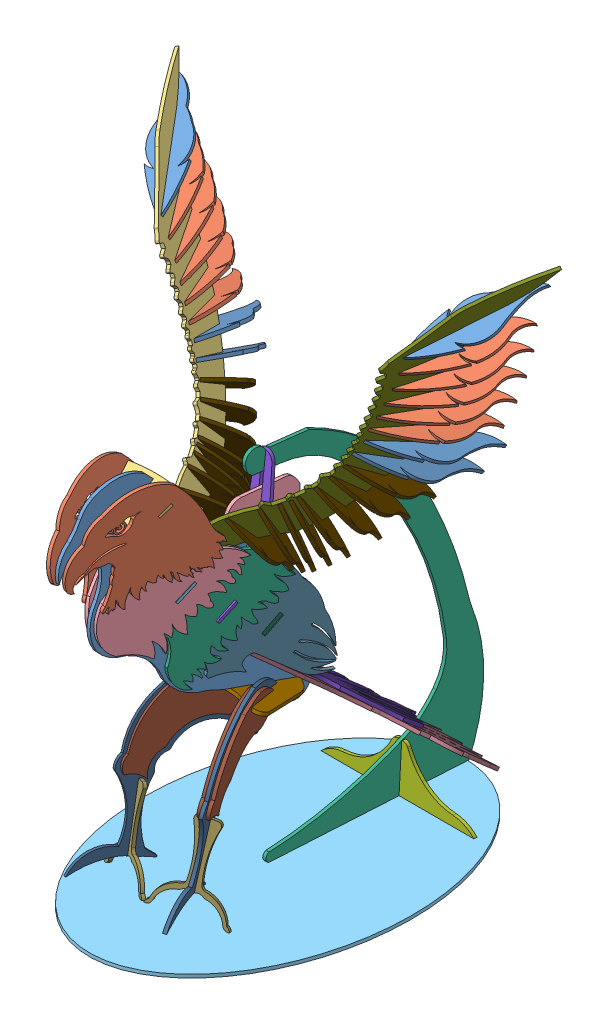
SolidWorks assembly _Assy, Eagle 03, configuration Default. Lengths in mm.
Overall size (190.84 278.18 211.69).
63 component instances, 26 part files, 130 mates.
Components (placement in the parent):
- Eagle-03-Face Plt-1: Eagle-03-Face Plt [Default] at (4.5464 2.0821 -8.328) size (1.52 133.89 123.29)
- Eagle-03-Face-3: Eagle-03-Face [Default] at (18.2617 -23.9605 -54.6337) x (0.981866 -0.103641 0.158737) z (-0.158737 0.008301 0.987286) size (1.52 51.83 68.44)
- Eagle-03-Face Plt, Connector-1: Eagle-03-Face Plt, Connector [Default] at (4.5464 6.6649 -5.3358) x (1 0 0) z (0 0.837329 0.546699) size (25.62 23.51 1.52)
- Eagle-03-Face-4: Eagle-03-Face [Default] at (-8.9705 -24.1185 -54.3918) x (0.981866 0.103641 -0.158737) z (0.158737 0.008301 0.987286) size (1.52 51.83 68.44)
- Part3^_Assy, Eagle 03-1: Part3^_Assy, Eagle 03 [Default] at (18.2617 -23.9605 -54.6337) x (-0.158737 0.008301 0.987286) z (-0.981866 0.103641 -0.158737) size (64.01 49.83 1.52) (virtual)
- Part4^_Assy, Eagle 03-1: Part4^_Assy, Eagle 03 [Default] at (4.5464 -26.2675 -30.5298) x (-1 0 0) z (0 -0.7873 -0.61657) size (21.81 39.99 1.52) (virtual)
- Part5^_Assy, Eagle 03-1: Part5^_Assy, Eagle 03 [Default] at (16.7654 -23.8026 -54.8756) x (-0.158737 0.008301 0.987286) z (-0.981866 0.103641 -0.158737) size (61.68 57.86 1.52) (virtual)
- MirrorPart5^_Assy, Eagle 03-2: MirrorPart5^_Assy, Eagle 03 [Default] at (-6.1486 -23.8026 -54.8756) x (0.158737 0.008301 0.987286) z (-0.981866 -0.103641 0.158737) size (61.68 57.86 1.52) (virtual)
- Part3^_Assy, Eagle 03-2: Part3^_Assy, Eagle 03 [Default] at (-6.1486 -23.8026 -54.8756) x (0.158737 0.008301 0.987286) z (-0.981866 -0.103641 0.158737) size (64.01 49.83 1.52) (virtual)
- Part7^_Assy, Eagle 03-1: Part7^_Assy, Eagle 03 [Default] at (4.5464 -45.8899 -47.7408) x (-1 0 0) z (0 -0.772669 -0.63481) size (23.73 45.97 1.52) (virtual)
- Part9^_Assy, Eagle 03-1: Part9^_Assy, Eagle 03 [Default] at (4.5464 -62.0946 14.0717) x (1 0 0) z (0 0.944143 -0.329537) size (40.67 40.1 1.52) (virtual)
- Part10^_Assy, Eagle 03-1: Part10^_Assy, Eagle 03 [Default] at (41.0348 -67.1746 -0.4828) x (0 -0.944143 0.329537) z (0.921165 -0.128247 -0.367435) size (82.99 56.69 1.52) (virtual)
- Part11^_Assy, Eagle 03-1: Part11^_Assy, Eagle 03 [Default] at (42.4386 -67.37 -1.0428) x (0 -0.944143 0.329537) z (0.921165 -0.128247 -0.367435) size (42.47 43.2 1.52) (virtual)
- Part12^_Assy, Eagle 03-1: Part12^_Assy, Eagle 03 [Default] at (22.8492 -76.282 -42.8953) x (0.044494 0.972658 -0.227942) z (0.386621 0.193623 0.901684) size (38.71 31.92 1.52) (virtual)
- Part11^_Assy, Eagle 03-2: Part11^_Assy, Eagle 03 [Default] at (-33.2257 -67.5654 -1.6027) x (0 -0.944143 0.329537) z (0.921165 0.128247 0.367435) size (42.47 43.2 1.52) (virtual)
- Part10^_Assy, Eagle 03-2: Part10^_Assy, Eagle 03 [Default] at (-31.8218 -67.37 -1.0428) x (0 -0.944143 0.329537) z (0.921165 0.128247 0.367435) size (82.99 56.69 1.52) (virtual)
- Part12^_Assy, Eagle 03-2: Part12^_Assy, Eagle 03 [Default] at (-12.8217 -75.9869 -41.5211) x (-0.044494 0.972658 -0.227942) z (0.386621 -0.193623 -0.901684) size (38.71 31.92 1.52) (virtual)
- Part11^_Assy, Eagle 03-3: Part11^_Assy, Eagle 03 [Default] at (39.9279 -66.7475 0.7408) x (0 -0.944143 0.329537) z (0.921165 -0.128247 -0.367435) size (42.47 43.2 1.52) (virtual)
- Part11^_Assy, Eagle 03-4: Part11^_Assy, Eagle 03 [Default] at (-30.7149 -66.9429 0.1808) x (0 -0.944143 0.329537) z (0.921165 0.128247 0.367435) size (42.47 43.2 1.52) (virtual)
- Eagle-03-Tail Feathers-1: Eagle-03-Tail Feathers [Default] at (5.3141 -107.6736 -104.5479) x (1 0.000049 0.000057) z (0 0.75999 -0.649935) size (91.35 114.83 1.52)
- Part13^_Assy, Eagle 03-1: Part13^_Assy, Eagle 03 [Default] at (15.269 -23.6446 -55.1175) x (-0.158737 0.008301 0.987286) z (-0.981866 0.103641 -0.158737) size (63.31 61.71 1.52) (virtual)
- Part13^_Assy, Eagle 03-2: Part13^_Assy, Eagle 03 [Default] at (-3.1558 -23.4867 -55.3594) x (0.158737 0.008301 0.987286) z (-0.981866 -0.103641 0.158737) size (63.31 61.71 1.52) (virtual)
- Part14^_Assy, Eagle 03-1: Part14^_Assy, Eagle 03 [Default] at (4.5464 -63.6501 -66.7331) x (-1 0 0) z (0 -0.747542 -0.664215) size (19.33 35.27 2.54) (virtual)
- Eagle-03-Wing-1: Eagle-03-Wing [Default] at (47.6613 31.141 -82.0922) x (0.53253 0.453967 -0.714371) z (0.845247 -0.32948 0.420715) size (164.91 76.09 1.52)
- Part6^_Assy, Eagle 03-1: Part6^_Assy, Eagle 03 [Default] at (5.3141 -106.5154 -105.5384) x (1 0.000049 0.000057) z (0 0.75999 -0.649935) size (56.42 90.79 1.52) (virtual)
- Eagle-03-Wing, Feather 01-1: Eagle-03-Wing, Feather 01 [Default] at (27.2198 17.4276 -51.7634) x (-0.845247 0.32948 -0.420715) z (0.523324 0.351078 -0.776451) size (16.36 41.94 1.52)
- Eagle-03-Wing, Feather 01-2: Eagle-03-Wing, Feather 01 [Default] at (29.1257 18.0081 -55.1379) x (-0.845247 0.32948 -0.420715) z (0.533315 0.470534 -0.702974) size (16.36 41.94 1.52)
- Eagle-03-Wing, Feather 01-5: Eagle-03-Wing, Feather 01 [Default] at (31.1805 19.9433 -57.7505) x (-0.845247 0.32948 -0.420715) z (0.532756 0.58084 -0.615464) size (16.36 41.94 1.52)
- Eagle-03-Wing, Feather 01-6: Eagle-03-Wing, Feather 01 [Default] at (33.1888 22.3762 -59.88) x (-0.845247 0.32948 -0.420715) z (0.521633 0.679638 -0.515744) size (16.36 41.94 1.52)
- Eagle-03-Wing, Feather 01-7: Eagle-03-Wing, Feather 01 [Default] at (35.1835 24.952 -61.8704) x (-0.845247 0.32948 -0.420715) z (0.50015 0.765007 -0.405727) size (16.36 41.94 1.52)
- Eagle-03-Wing, Feather 02-1: Eagle-03-Wing, Feather 02 [Default] at (37.2021 27.7302 -63.7501) x (-0.845247 0.32948 -0.420715) z (0.468765 0.835141 -0.287748) size (17.91 55.77 1.52)
- Eagle-03-Wing, Feather 02-2: Eagle-03-Wing, Feather 02 [Default] at (39.2678 30.7754 -65.5155) x (-0.845247 0.32948 -0.420715) z (0.428068 0.88874 -0.164008) size (17.91 55.77 1.52)
- Eagle-03-Wing, Feather 03-1: Eagle-03-Wing, Feather 03 [Default] at (41.4186 34.1243 -67.2139) x (-0.845247 0.32948 -0.420715) z (0.378864 0.924713 -0.036982) size (16.4 49.51 1.52)
- Eagle-03-Wing, Feather 03-2: Eagle-03-Wing, Feather 03 [Default] at (43.5314 37.9912 -68.4303) x (-0.845247 0.32948 -0.420715) z (0.322091 0.942336 0.090881) size (16.4 49.51 1.52)
- Eagle-03-Wing, Feather 03-3: Eagle-03-Wing, Feather 03 [Default] at (45.8003 42.2995 -69.6147) x (-0.845247 0.32948 -0.420715) z (0.259027 0.941242 0.216723) size (16.4 49.51 1.52)
- Eagle-03-Wing, Feather 03-4: Eagle-03-Wing, Feather 03 [Default] at (48.4967 47.3173 -71.1023) x (-0.845247 0.32948 -0.420715) z (0.190776 0.921474 0.338364) size (16.4 49.51 1.52)
- Eagle-03-Wing, Feather 03-5: Eagle-03-Wing, Feather 03 [Default] at (51.3336 53.2849 -72.1283) x (-0.845247 0.32948 -0.420715) z (0.118763 0.883435 0.453253) size (16.4 49.51 1.52)
- Eagle-03-Wing, Feather 02-4: Eagle-03-Wing, Feather 02 [Default] at (52.8567 58.4319 -71.1574) x (-0.845247 0.32948 -0.420715) z (0.044381 0.827863 0.559172) size (17.91 55.77 1.52)
- Eagle-03-Wing, Feather 01-8: Eagle-03-Wing, Feather 01 [Default] at (14.8649 11.7304 -31.4033) x (-0.845247 0.32948 -0.420715) z (0.532146 0.590827 -0.606419) size (16.36 41.94 1.52)
- Eagle-03-Wing, Feather 01-9: Eagle-03-Wing, Feather 01 [Default] at (22.8616 16.0279 -44.1037) x (-0.845247 0.32948 -0.420715) z (0.530699 0.425366 -0.733091) size (16.36 41.94 1.52)
- Eagle-03-Wing, Feather 01-10: Eagle-03-Wing, Feather 01 [Default] at (28.7032 17.932 -54.3485) x (-0.845247 0.32948 -0.420715) z (0.527566 0.389225 -0.755101) size (16.36 41.94 1.52)
- MirrorEagle-03-Wing-2: MirrorEagle-03-Wing [Default] at (-37.0445 31.141 -82.0922) x (-0.53253 0.453967 -0.714371) z (0.845247 0.32948 -0.420715) size (164.91 76.09 1.52)
- Eagle-03-Wing, Feather 01-11: Eagle-03-Wing, Feather 01 [Default] at (-5.0591 12.6308 -32.3274) x (0.845247 0.32948 -0.420715) z (0.532146 -0.590827 0.606419) size (16.36 41.94 1.52)
- Eagle-03-Wing, Feather 01-12: Eagle-03-Wing, Feather 01 [Default] at (-13.0536 16.6761 -45.221) x (0.845247 0.32948 -0.420715) z (0.530699 -0.425366 0.733091) size (16.36 41.94 1.52)
- Eagle-03-Wing, Feather 01-13: Eagle-03-Wing, Feather 01 [Default] at (-17.4006 17.9627 -52.9467) x (0.845247 0.32948 -0.420715) z (0.523324 -0.351078 0.776451) size (16.36 41.94 1.52)
- Eagle-03-Wing, Feather 01-14: Eagle-03-Wing, Feather 01 [Default] at (-18.8904 18.5252 -55.4993) x (0.845247 0.32948 -0.420715) z (0.527566 -0.389225 0.755101) size (16.36 41.94 1.52)
- Eagle-03-Wing, Feather 01-15: Eagle-03-Wing, Feather 01 [Default] at (-19.3217 18.7252 -56.2092) x (0.845247 0.32948 -0.420715) z (0.533315 -0.470534 0.702974) size (16.36 41.94 1.52)
- Eagle-03-Wing, Feather 01-16: Eagle-03-Wing, Feather 01 [Default] at (-21.3756 20.8285 -58.6885) x (0.845247 0.32948 -0.420715) z (0.532756 -0.58084 0.615464) size (16.36 41.94 1.52)
- Eagle-03-Wing, Feather 01-17: Eagle-03-Wing, Feather 01 [Default] at (-23.367 23.412 -60.666) x (0.845247 0.32948 -0.420715) z (0.521633 -0.679638 0.515744) size (16.36 41.94 1.52)
- Eagle-03-Wing, Feather 01-18: Eagle-03-Wing, Feather 01 [Default] at (-25.329 26.1179 -62.4888) x (0.845247 0.32948 -0.420715) z (0.50015 -0.765007 0.405727) size (16.36 41.94 1.52)
- Eagle-03-Wing, Feather 02-5: Eagle-03-Wing, Feather 02 [Default] at (-27.2997 29.0029 -64.1886) x (0.845247 0.32948 -0.420715) z (0.468765 -0.835141 0.287748) size (17.91 55.77 1.52)
- Eagle-03-Wing, Feather 02-6: Eagle-03-Wing, Feather 02 [Default] at (-29.3034 32.1298 -65.7655) x (0.845247 0.32948 -0.420715) z (0.428068 -0.88874 0.164008) size (17.91 55.77 1.52)
- Eagle-03-Wing, Feather 03-6: Eagle-03-Wing, Feather 03 [Default] at (-31.3792 35.5335 -67.2703) x (0.845247 0.32948 -0.420715) z (0.378864 -0.924713 0.036982) size (16.4 49.51 1.52)
- Eagle-03-Wing, Feather 03-7: Eagle-03-Wing, Feather 03 [Default] at (-35.5783 43.734 -69.2845) x (0.845247 0.32948 -0.420715) z (0.259027 -0.941242 -0.216723) size (16.4 49.51 1.52)
- Eagle-03-Wing, Feather 03-8: Eagle-03-Wing, Feather 03 [Default] at (-33.4055 39.4273 -68.2918) x (0.845247 0.32948 -0.420715) z (0.322091 -0.942336 -0.090881) size (16.4 49.51 1.52)
- Eagle-03-Wing, Feather 03-9: Eagle-03-Wing, Feather 03 [Default] at (-38.1706 48.7216 -70.5866) x (0.845247 0.32948 -0.420715) z (0.190776 -0.921474 -0.338364) size (16.4 49.51 1.52)
- Eagle-03-Wing, Feather 03-10: Eagle-03-Wing, Feather 03 [Default] at (-40.8978 54.6313 -71.4375) x (0.845247 0.32948 -0.420715) z (0.118763 -0.883435 -0.453253) size (16.4 49.51 1.52)
- Eagle-03-Wing, Feather 02-7: Eagle-03-Wing, Feather 02 [Default] at (-42.3075 59.6936 -70.3053) x (0.845247 0.32948 -0.420715) z (0.044381 -0.827863 -0.559172) size (17.91 55.77 1.52)
- Part8^_Assy, Eagle 03-1: Part8^_Assy, Eagle 03 [Default] at (6.0704 2.0821 -8.328) x (0 0 -1) z (1 0 0) size (46.26 26.4 1.52) (virtual)
- Eagle-03-Base-1: Eagle-03-Base [Default] at (5.3084 -168.7529 -81.7321) x (1 0 0) z (0 0.05588 0.998437) size (112.54 1.52 180.18)
- Part15^_Assy, Eagle 03-1: Part15^_Assy, Eagle 03 [Default] at (4.5464 -168.7529 -81.7321) x (0 -0.05588 -0.998437) z (1 0 0) size (121.63 175.4 1.52) (virtual)
- Part16^_Assy, Eagle 03-1: Part16^_Assy, Eagle 03 [Default] at (4.5464 -172.0376 -140.4203) x (1 0 0) z (0 0.05588 0.998437) size (72.95 22.35 1.52) (virtual)
- Part17^_Assy, Eagle 03-1: Part17^_Assy, Eagle 03 [Default] at (4.5464 -165.8304 -56.0297) x (-1 0 0) z (0 -0.112979 -0.993597) size (10.18 28.23 1.52) (virtual)
Mates (geometry in assembly coordinates):
- InPlace1: in place: plane of Eagle-03-Face Plt-1 through (6.0704 18.1227 -23.154) normal (0 0.837329 0.546699); plane of ? through (0 2.1071 1.3757) normal (0 0.837329 0.546699); moOrthogonalPlaneRef_w of Eagle-03-Face Plt-1 through (6.0704 18.1227 -23.154) normal (0 0.837329 0.546699); plane of ? through (0 2.1071 1.3757) normal (0 0.546699 -0.837329); plane of Eagle-03-Face Plt-1 through (6.0704 18.1227 -23.154) normal (0 0.837329 0.546699); unknown of ?; plane of Eagle-03-Face Plt-1 through (6.0704 18.0306 -22.7436) normal (0 0.837329 0.546699); unknown of Eagle-03-Face Plt, Connector-1
- Coincident1: coincident aligned: plane of Eagle-03-Face Plt-1; plane of Eagle-03-Face Plt, Connector-1
- Coincident2: coincident aligned: moOrthogonalPlaneRef_w of Eagle-03-Face Plt-1 through (4.5464 6.6649 -5.3358) normal (0 0.546699 -0.837329); plane of Eagle-03-Face Plt, Connector-1 through (4.5464 6.6649 -5.3358) normal (0 0.546699 -0.837329)
- Coincident3: coincident anti-aligned: moOrthogonalPlaneRef_w of Eagle-03-Face Plt-1 through (4.5464 6.6649 -5.3358) normal (-1 0 0); plane of Eagle-03-Face Plt, Connector-1
- Coincident4: coincident anti-aligned: plane of Eagle-03-Face-3 through (17.054 12.2638 -13.9111) normal (0.189575 0.536786 -0.822145); plane of Eagle-03-Face Plt, Connector-1 through (15.5576 13.6978 -13.3199) normal (-0.189575 -0.536786 0.822145)
- Coincident5: coincident anti-aligned: plane of Eagle-03-Face-3 through (18.231 15.5967 -19.0158) normal (0 0.837329 0.546699); plane of Eagle-03-Face Plt, Connector-1 through (5.3938 -29.841 50.5768) normal (0 -0.837329 -0.546699)
- Coincident6: coincident aligned: plane of Eagle-03-Face-3 through (15.2141 -12.4677 -18.6782) normal (0.981866 -0.103641 0.158737); plane of Eagle-03-Face Plt, Connector-1 through (17.054 13.5399 -13.0779) normal (0.981866 -0.103641 0.158737)
- Coincident7: coincident anti-aligned: plane of Eagle-03-Face Plt, Connector-1 through (-2.5722 7.4746 -3.7883) normal (-0.981866 -0.103641 0.158737); plane of Eagle-03-Face-4 through (-2.9302 -12.3098 -18.9201) normal (0.981866 0.103641 -0.158737)
- Coincident8: coincident anti-aligned: plane of Eagle-03-Face Plt, Connector-1 through (5.3938 -28.5649 51.41) normal (0 0.837329 0.546699); plane of Eagle-03-Face-4 through (-4.77 13.6978 -13.3199) normal (0 -0.837329 -0.546699)
- Coincident10: coincident anti-aligned: plane of Eagle-03-Face Plt, Connector-1 through (-4.77 13.6978 -13.3199) normal (0.189575 -0.536786 0.822145); plane of Eagle-03-Face-4 through (-4.77 12.4217 -14.153) normal (-0.189575 0.536786 -0.822145)
- InPlace2: in place: plane of ? through (12.1937 -12.3098 -18.9201) normal (-0.981866 0.103641 -0.158737); plane of ? through (10.0593 -1.0618 1.6263) normal (-0.981866 0.103641 -0.158737); plane of ? through (12.1937 -12.3098 -18.9201) normal (-0.981866 0.103641 -0.158737); unknown of ?; plane of ? through (12.1937 -12.3098 -18.9201) normal (-0.981866 0.103641 -0.158737); unknown of ?; plane of Eagle-03-Face-3 through (13.7177 -12.3098 -18.9201) normal (-0.981866 0.103641 -0.158737); unknown of Part3^_Assy, Eagle 03-1
- Coincident12: coincident aligned: plane of Eagle-03-Face-3; plane of Part3^_Assy, Eagle 03-1
- Coincident13: coincident aligned: moOrthogonalPlaneRef_w of Eagle-03-Face-3 through (18.2617 -23.9605 -54.6337) normal (0.103641 0.99458 0.008301); plane of Part3^_Assy, Eagle 03-1
- Coincident14: coincident anti-aligned: moOrthogonalPlaneRef_w of Eagle-03-Face-3 through (18.2617 -23.9605 -54.6337) normal (0.158737 -0.008301 -0.987286); plane of Part3^_Assy, Eagle 03-1
- InPlace3: in place: plane of Eagle-03-Face Plt-1 through (6.0704 -14.2584 -45.8643) normal (0 -0.7873 -0.61657); plane of ? through (0 -31.1016 -24.3571) normal (0 -0.7873 -0.61657); plane of Eagle-03-Face Plt-1 through (6.0704 -14.2584 -45.8643) normal (0 -0.7873 -0.61657); unknown of ?; plane of Eagle-03-Face Plt-1 through (6.0704 -14.2584 -45.8643) normal (0 -0.7873 -0.61657); unknown of ?; plane of Eagle-03-Face Plt-1 through (6.0704 -14.2584 -45.8643) normal (0 -0.7873 -0.61657); unknown of Part4^_Assy, Eagle 03-1
- Coincident15: coincident aligned: plane of Eagle-03-Face Plt-1; plane of Part4^_Assy, Eagle 03-1
- Coincident16: coincident aligned: moOrthogonalPlaneRef_w of Eagle-03-Face Plt-1 through (4.5464 -26.2675 -30.5298) normal (0 0.61657 -0.7873); plane of Part4^_Assy, Eagle 03-1
- Coincident17: coincident anti-aligned: moOrthogonalPlaneRef_w of Eagle-03-Face Plt-1 through (4.5464 -26.2675 -30.5298) normal (1 0 0); plane of Part4^_Assy, Eagle 03-1
- InPlace4: in place: plane of Part3^_Assy, Eagle 03-1 through (5.6608 -52.0671 -4.6424) normal (-0.981866 0.103641 -0.158737); plane of ? through (10.0322 -1.0589 1.6219) normal (-0.981866 0.103641 -0.158737); plane of Part3^_Assy, Eagle 03-1 through (5.6608 -52.0671 -4.6424) normal (-0.981866 0.103641 -0.158737); unknown of ?; plane of Part3^_Assy, Eagle 03-1 through (5.6608 -52.0671 -4.6424) normal (-0.981866 0.103641 -0.158737); unknown of ?; plane of Part3^_Assy, Eagle 03-1 through (5.6608 -52.0671 -4.6424) normal (-0.981866 0.103641 -0.158737); unknown of Part5^_Assy, Eagle 03-1
- Coincident18: coincident aligned: plane of Part3^_Assy, Eagle 03-1; plane of Part5^_Assy, Eagle 03-1
- Coincident19: coincident aligned: moOrthogonalPlaneRef_w of Part3^_Assy, Eagle 03-1 through (16.7654 -23.8026 -54.8756) normal (0.103641 0.99458 0.008301); plane of Part5^_Assy, Eagle 03-1
- Coincident20: coincident anti-aligned: moOrthogonalPlaneRef_w of Part3^_Assy, Eagle 03-1 through (16.7654 -23.8026 -54.8756) normal (0.158737 -0.008301 -0.987286); plane of Part5^_Assy, Eagle 03-1
- InPlace5: in place: plane of Eagle-03-Face Plt-1 through (6.0704 -29.5323 -67.6507) normal (0 -0.772669 -0.63481); plane of ? through (0 -50.8138 -41.7476) normal (0 -0.772669 -0.63481); plane of Eagle-03-Face Plt-1 through (6.0704 -29.5323 -67.6507) normal (0 -0.772669 -0.63481); unknown of ?; plane of Eagle-03-Face Plt-1 through (6.0704 -29.5323 -67.6507) normal (0 -0.772669 -0.63481); unknown of ?; plane of Eagle-03-Face Plt-1 through (6.0704 -29.5323 -67.6507) normal (0 -0.772669 -0.63481); unknown of Part7^_Assy, Eagle 03-1
- Coincident21: coincident aligned: plane of Eagle-03-Face Plt-1; plane of Part7^_Assy, Eagle 03-1
- Coincident22: coincident aligned: moOrthogonalPlaneRef_w of Eagle-03-Face Plt-1 through (4.5464 -45.8899 -47.7408) normal (0 0.63481 -0.772669); plane of Part7^_Assy, Eagle 03-1
- Coincident23: coincident anti-aligned: moOrthogonalPlaneRef_w of Eagle-03-Face Plt-1 through (4.5464 -45.8899 -47.7408) normal (1 0 0); plane of Part7^_Assy, Eagle 03-1
- InPlace7: in place: plane of Eagle-03-Face Plt-1 through (6.0704 -89.3653 -64.0608) normal (0 0.944143 -0.329537); plane of ? through (0 -59.7296 20.8476) normal (0 0.944143 -0.329537); plane of Eagle-03-Face Plt-1 through (6.0704 -89.3653 -64.0608) normal (0 0.944143 -0.329537); plane of ? through (0 -59.7296 20.8476) normal (0 -0.329537 -0.944143); plane of Eagle-03-Face Plt-1 through (6.0704 -89.3653 -64.0608) normal (0 0.944143 -0.329537); unknown of ?; plane of Eagle-03-Face Plt-1 through (6.0704 -89.3653 -64.0608) normal (0 0.944143 -0.329537); unknown of Part9^_Assy, Eagle 03-1
- Coincident27: coincident aligned: plane of Eagle-03-Face Plt-1; plane of Part9^_Assy, Eagle 03-1
- Coincident28: coincident aligned: moOrthogonalPlaneRef_w of Eagle-03-Face Plt-1 through (4.5464 -62.0946 14.0717) normal (0 -0.329537 -0.944143); plane of Part9^_Assy, Eagle 03-1 through (4.5464 -62.0946 14.0717) normal (0 -0.329537 -0.944143)
- Coincident29: coincident anti-aligned: moOrthogonalPlaneRef_w of Eagle-03-Face Plt-1 through (4.5464 -62.0946 14.0717) normal (-1 0 0); plane of Part9^_Assy, Eagle 03-1
- InPlace8: in place: plane of Part9^_Assy, Eagle 03-1 through (16.3358 -84.8911 -55.8665) normal (0.951578 -0.101302 -0.290237); plane of ? through (38.4047 -4.0884 -11.7136) normal (0.951578 -0.101302 -0.290237); plane of Part9^_Assy, Eagle 03-1 through (16.3358 -84.8911 -55.8665) normal (0.951578 -0.101302 -0.290237); unknown of ?; plane of Part9^_Assy, Eagle 03-1 through (16.3358 -84.8911 -55.8665) normal (0.951578 -0.101302 -0.290237); unknown of ?; plane of Part9^_Assy, Eagle 03-1 through (15.8464 -85.3827 -57.2751) normal (0.921165 -0.128247 -0.367435); unknown of Part10^_Assy, Eagle 03-1
- Coincident30: coincident aligned: plane of Part9^_Assy, Eagle 03-1; plane of Part10^_Assy, Eagle 03-1
- Coincident31: coincident aligned: moOrthogonalPlaneRef_w of Part9^_Assy, Eagle 03-1; plane of Part10^_Assy, Eagle 03-1
- Coincident32: coincident anti-aligned: moOrthogonalPlaneRef_w of Part9^_Assy, Eagle 03-1 through (41.0348 -67.1746 -0.4828) normal (0 0.944143 -0.329537); plane of Part10^_Assy, Eagle 03-1
- InPlace9: in place: plane of ? through (16.1722 -87.6882 -60.6776) normal (0.951578 -0.101302 -0.290237); plane of ? through (39.8549 -4.2428 -12.156) normal (0.951578 -0.101302 -0.290237); plane of ? through (16.1722 -87.6882 -60.6776) normal (0.951578 -0.101302 -0.290237); unknown of ?; plane of ? through (16.1722 -87.6882 -60.6776) normal (0.951578 -0.101302 -0.290237); unknown of ?; plane of Part10^_Assy, Eagle 03-1 through (14.5705 -88.6649 -63.4758) normal (0.921165 -0.128247 -0.367435); unknown of Part11^_Assy, Eagle 03-1
- Coincident33: coincident aligned: plane of Part10^_Assy, Eagle 03-1; plane of Part11^_Assy, Eagle 03-1
- Coincident34: coincident aligned: moOrthogonalPlaneRef_w of Part10^_Assy, Eagle 03-1; plane of Part11^_Assy, Eagle 03-1
- Coincident35: coincident anti-aligned: moOrthogonalPlaneRef_w of Part10^_Assy, Eagle 03-1 through (42.4386 -67.37 -1.0428) normal (0 0.944143 -0.329537); plane of Part11^_Assy, Eagle 03-1
- InPlace10: in place: plane of ? through (21.2884 -145.4075 -23.7574) normal (0.305392 0.20358 0.93021); plane of ? through (-13.8038 -9.2018 -42.0456) normal (0.305392 0.20358 0.93021); plane of ? through (21.2884 -145.4075 -23.7574) normal (0.305392 0.20358 0.93021); unknown of ?; plane of ? through (21.2884 -145.4075 -23.7574) normal (0.305392 0.20358 0.93021); unknown of ?; plane of Part10^_Assy, Eagle 03-1 through (21.0476 -146.551 -27.0336) normal (0.386621 0.193623 0.901684); unknown of Part12^_Assy, Eagle 03-1
- Coincident36: coincident aligned: plane of Part10^_Assy, Eagle 03-1; plane of Part12^_Assy, Eagle 03-1
- Coincident37: coincident aligned: moOrthogonalPlaneRef_w of Part10^_Assy, Eagle 03-1; plane of Part12^_Assy, Eagle 03-1
- Coincident38: coincident anti-aligned: moOrthogonalPlaneRef_w of Part10^_Assy, Eagle 03-1; plane of Part12^_Assy, Eagle 03-1
- Coincident39: coincident anti-aligned: plane of Part9^_Assy, Eagle 03-1 through (15.8464 -85.3827 -57.2751) normal (0.389173 0.303557 0.869711); plane of Part11^_Assy, Eagle 03-3 through (15.8464 -86.8216 -56.7728) normal (-0.389173 -0.303557 -0.869711)
- Coincident40: coincident anti-aligned: plane of Part9^_Assy, Eagle 03-1 through (4.9537 -79.553 -40.5726) normal (0 0.944143 -0.329537); plane of Part11^_Assy, Eagle 03-3 through (15.8464 -85.3827 -57.2751) normal (0 -0.944143 0.329537)
- Coincident41: coincident anti-aligned: plane of Part10^_Assy, Eagle 03-1 through (13.1667 -88.4695 -62.9159) normal (-0.921165 0.128247 0.367435); plane of Part11^_Assy, Eagle 03-3 through (14.8711 -109.3754 -51.3459) normal (0.921165 -0.128247 -0.367435)
- Coincident42: coincident anti-aligned: plane of Eagle-03-Face Plt-1 through (4.5464 -30.2496 34.0896) normal (-1 0 0); plane of Eagle-03-Tail Feathers-1 through (4.5464 -72.9892 -66.3352) normal (1 0 0)
- Coincident43: coincident anti-aligned: plane of Eagle-03-Face Plt-1 through (6.0704 -101.0949 -96.8552) normal (0 0.75999 -0.649935); plane of Eagle-03-Tail Feathers-1 through (-41.7004 -77.4909 -69.2543) normal (0 -0.75999 0.649935)
- Coincident44: coincident anti-aligned: plane of Eagle-03-Face Plt-1 through (6.0704 -85.7615 -81.2702) normal (0 -0.649935 -0.75999); plane of Eagle-03-Tail Feathers-1 through (6.0704 -85.7615 -81.2702) normal (0 0.649935 0.75999)
- InPlace11: in place: plane of Part5^_Assy, Eagle 03-1 through (-1.8013 -85.7758 9.9045) normal (-0.981866 0.103641 -0.158737); plane of ? through (8.5358 -0.901 1.38) normal (-0.981866 0.103641 -0.158737); plane of Part5^_Assy, Eagle 03-1 through (-1.8013 -85.7758 9.9045) normal (-0.981866 0.103641 -0.158737); unknown of ?; plane of Part5^_Assy, Eagle 03-1 through (-1.8013 -85.7758 9.9045) normal (-0.981866 0.103641 -0.158737); unknown of ?; plane of Part5^_Assy, Eagle 03-1 through (-1.8013 -85.7758 9.9045) normal (-0.981866 0.103641 -0.158737); unknown of Part13^_Assy, Eagle 03-1
- Coincident45: coincident aligned: plane of Part5^_Assy, Eagle 03-1; plane of Part13^_Assy, Eagle 03-1
- Coincident46: coincident aligned: moOrthogonalPlaneRef_w of Part5^_Assy, Eagle 03-1 through (15.269 -23.6446 -55.1175) normal (0.103641 0.99458 0.008301); plane of Part13^_Assy, Eagle 03-1
- Coincident47: coincident anti-aligned: moOrthogonalPlaneRef_w of Part5^_Assy, Eagle 03-1 through (15.269 -23.6446 -55.1175) normal (0.158737 -0.008301 -0.987286); plane of Part13^_Assy, Eagle 03-1
- InPlace12: in place: plane of Eagle-03-Face Plt-1 through (6.0704 -48.3979 -83.8987) normal (0 -0.747542 -0.664215); plane of ? through (0 -68.7037 -61.0455) normal (0 -0.747542 -0.664215); plane of Eagle-03-Face Plt-1 through (6.0704 -48.3979 -83.8987) normal (0 -0.747542 -0.664215); unknown of ?; plane of Eagle-03-Face Plt-1 through (6.0704 -48.3979 -83.8987) normal (0 -0.747542 -0.664215); unknown of ?; plane of Eagle-03-Face Plt-1 through (6.0704 -48.3979 -83.8987) normal (0 -0.747542 -0.664215); unknown of Part14^_Assy, Eagle 03-1
- Coincident45: coincident aligned: plane of Eagle-03-Face Plt-1; plane of Part14^_Assy, Eagle 03-1
- Coincident46: coincident aligned: moOrthogonalPlaneRef_w of Eagle-03-Face Plt-1 through (4.5464 -63.6501 -66.7331) normal (0 0.664215 -0.747542); plane of Part14^_Assy, Eagle 03-1
- Coincident47: coincident anti-aligned: moOrthogonalPlaneRef_w of Eagle-03-Face Plt-1 through (4.5464 -63.6501 -66.7331) normal (1 0 0); plane of Part14^_Assy, Eagle 03-1
- InPlace13: in place: plane of Eagle-03-Tail Feathers-1 through (-41.7004 -76.3327 -70.2448) normal (0 0.75999 -0.649935); plane of ? through (0 -9.3916 8.0316) normal (0 0.75999 -0.649935); plane of Eagle-03-Tail Feathers-1 through (-41.7004 -76.3327 -70.2448) normal (0 0.75999 -0.649935); plane of ? through (0 -9.3916 8.0316) normal (0 -0.649935 -0.75999); plane of Eagle-03-Tail Feathers-1 through (-41.7004 -76.3327 -70.2448) normal (0 0.75999 -0.649935); unknown of ?; plane of Eagle-03-Tail Feathers-1 through (-41.7004 -76.3327 -70.2448) normal (0 0.75999 -0.649935); unknown of Part6^_Assy, Eagle 03-1
- Coincident45: coincident aligned: plane of Eagle-03-Tail Feathers-1; plane of Part6^_Assy, Eagle 03-1
- Coincident46: coincident aligned: moOrthogonalPlaneRef_w of Eagle-03-Tail Feathers-1 through (5.3141 -106.5154 -105.5384) normal (0.000075 -0.649935 -0.75999); plane of Part6^_Assy, Eagle 03-1
- Coincident47: coincident anti-aligned: moOrthogonalPlaneRef_w of Eagle-03-Tail Feathers-1 through (5.3141 -106.5154 -105.5384) normal (-1 -0.000049 -0.000057); plane of Part6^_Assy, Eagle 03-1
- InPlace14: in place: plane of ? through (24.8011 -30.9094 -92.1987) normal (0.630171 0.330202 -0.702746); plane of ? through (44.2473 23.1851 -49.3432) normal (0.630171 0.330202 -0.702746); plane of ? through (24.8011 -30.9094 -92.1987) normal (0.630171 0.330202 -0.702746); unknown of ?; plane of ? through (24.8011 -30.9094 -92.1987) normal (0.630171 0.330202 -0.702746); unknown of ?; plane of Eagle-03-Wing-1 through (24.2107 -17.9092 -69.7694) normal (0.523324 0.351078 -0.776451); unknown of Eagle-03-Wing, Feather 01-1
- Coincident45: coincident aligned: plane of Eagle-03-Wing-1; plane of Eagle-03-Wing, Feather 01-1
- Coincident46: coincident aligned: moOrthogonalPlaneRef_w of Eagle-03-Wing-1; plane of Eagle-03-Wing, Feather 01-1
- Coincident47: coincident anti-aligned: moOrthogonalPlaneRef_w of Eagle-03-Wing-1; plane of Eagle-03-Wing, Feather 01-1
- Coincident48: coincident anti-aligned: plane of Eagle-03-Wing-1 through (29.2468 -10.8786 -74.3812) normal (0.533315 0.470534 -0.702974); plane of Eagle-03-Wing, Feather 01-2 through (88.0262 -52.6773 -57.7658) normal (-0.533315 -0.470534 0.702974)
- Coincident50: coincident: plane of Eagle-03-Wing-1 through (29.2468 -10.8786 -74.3812) normal (-0.033645 -0.818551 -0.573448); moEndPointRef_w of Eagle-03-Wing, Feather 01-2
- Coincident51: coincident anti-aligned: plane of Eagle-03-Wing-1 through (12.2922 -12.1744 -41.3331) normal (0.845247 -0.32948 0.420715); plane of Eagle-03-Wing, Feather 01-2 through (30.5339 1.3738 -67.3717) normal (-0.845247 0.32948 -0.420715)
- Coincident59: coincident: moEndPointRef_w of Eagle-03-Wing-1; plane of Eagle-03-Wing, Feather 01-5 through (34.7225 -5.4851 -81.1585) normal (-0.041585 0.744357 0.666486)
- Coincident60: coincident anti-aligned: plane of Eagle-03-Wing-1 through (11.0041 -11.6723 -41.9742) normal (-0.845247 0.32948 -0.420715); plane of Eagle-03-Wing, Feather 01-5 through (33.4344 -4.983 -81.7997) normal (0.845247 -0.32948 0.420715)
- Coincident61: coincident anti-aligned: plane of Eagle-03-Wing-1 through (34.7225 -5.4848 -81.1582) normal (-0.532756 -0.58084 0.615464); plane of Eagle-03-Wing, Feather 01-5 through (95.2105 -45.5989 -66.6562) normal (0.532756 0.58084 -0.615464)
- Coincident62: coincident anti-aligned: plane of Eagle-03-Wing-1 through (12.2922 -12.1744 -41.3331) normal (0.845247 -0.32948 0.420715); plane of Eagle-03-Wing, Feather 01-6 through (37.6598 9.4193 -75.3873) normal (-0.845247 0.32948 -0.420715)
- Coincident63: coincident anti-aligned: plane of Eagle-03-Wing-1 through (39.2946 0.1834 -85.9048) normal (-0.521633 -0.679638 0.515744); plane of Eagle-03-Wing, Feather 01-6 through (101.4726 -37.9099 -73.2155) normal (0.521633 0.679638 -0.515744)
- Coincident64: coincident: moEndPointRef_w of Eagle-03-Wing-1; plane of Eagle-03-Wing, Feather 01-6 through (39.2946 0.1834 -85.9047) normal (-0.116006 0.65539 0.746329)
- Coincident65: coincident anti-aligned: plane of Eagle-03-Wing-1 through (43.759 6.4273 -89.9842) normal (-0.50015 -0.765007 0.405727); plane of Eagle-03-Wing, Feather 01-7 through (107.5758 -29.349 -78.7729) normal (0.50015 0.765007 -0.405727)
- Coincident66: coincident anti-aligned: plane of Eagle-03-Wing-1 through (11.0041 -11.6723 -41.9742) normal (-0.845247 0.32948 -0.420715); plane of Eagle-03-Wing, Feather 01-7 through (42.4708 6.9295 -90.6254) normal (0.845247 -0.32948 0.420715)
- Coincident67: coincident: moEndPointRef_w of Eagle-03-Wing-1; plane of Eagle-03-Wing, Feather 01-7 through (43.759 6.4274 -89.9842) normal (-0.188171 0.553359 0.811409)
- Coincident74: coincident anti-aligned: plane of Eagle-03-Wing-1 through (11.0041 -11.6723 -41.9742) normal (-0.845247 0.32948 -0.420715); plane of Eagle-03-Wing, Feather 02-1 through (46.8126 13.7303 -94.0223) normal (0.845247 -0.32948 0.420715)
- Coincident75: coincident anti-aligned: plane of Eagle-03-Wing-1 through (48.1009 13.228 -93.3815) normal (-0.468765 -0.835141 0.287748); plane of Eagle-03-Wing, Feather 02-1 through (113.4703 -19.9838 -83.2812) normal (0.468765 0.835141 -0.287748)
- Coincident76: coincident: plane of Eagle-03-Wing-1 through (47.3723 11.9309 -92.9336) normal (0.256235 -0.440992 -0.860156); moEndPointRef_w of Eagle-03-Wing, Feather 02-1
- Coincident78: coincident anti-aligned: plane of Eagle-03-Wing-1 through (52.3 20.5758 -96.0636) normal (-0.428068 -0.88874 0.164008); plane of Eagle-03-Wing, Feather 02-2 through (119.1077 -9.8725 -86.6883) normal (0.428068 0.88874 -0.164008)
- Coincident79: coincident: moEndPointRef_w of Eagle-03-Wing-1; plane of Eagle-03-Wing, Feather 02-2 through (52.3002 20.5756 -96.0639) normal (-0.319869 0.318721 0.892245)
- Coincident80: coincident anti-aligned: plane of Eagle-03-Wing-1 through (11.0041 -11.6723 -41.9742) normal (-0.845247 0.32948 -0.420715); plane of Eagle-03-Wing, Feather 02-2 through (51.012 21.0778 -96.7051) normal (0.845247 -0.32948 0.420715)
- Coincident84: coincident anti-aligned: plane of Eagle-03-Wing-1 through (55.7747 27.0111 -98.0046) normal (0.378864 0.924713 -0.036982); plane of Eagle-03-Wing, Feather 03-1 through (124.1463 -0.3988 -82.936) normal (-0.378864 -0.924713 0.036982)
- Coincident85: coincident anti-aligned: plane of Eagle-03-Wing-1 through (11.0041 -11.6723 -41.9742) normal (-0.845247 0.32948 -0.420715); plane of Eagle-03-Wing, Feather 03-1 through (55.0639 28.9224 -98.7022) normal (0.845247 -0.32948 0.420715)
- Coincident86: coincident: moEndPointRef_w of Eagle-03-Wing-1; plane of Eagle-03-Wing, Feather 03-1 through (56.3521 28.4203 -98.061) normal (-0.376856 0.190652 0.906439)
- Coincident87: coincident anti-aligned: plane of Eagle-03-Wing-1 through (60.0968 36.8899 -98.9514) normal (-0.322091 -0.942336 -0.090881); plane of Eagle-03-Wing, Feather 03-2 through (129.3266 11.7674 -83.8157) normal (0.322091 0.942336 0.090881)
- Coincident88: coincident: moEndPointRef_w of Eagle-03-Wing-1; plane of Eagle-03-Wing, Feather 03-2 through (60.0963 36.89 -98.9504) normal (-0.426398 0.058692 0.902629)
- Coincident89: coincident anti-aligned: plane of Eagle-03-Wing-1 through (11.0041 -11.6723 -41.9742) normal (-0.845247 0.32948 -0.420715); plane of Eagle-03-Wing, Feather 03-2 through (58.8081 37.3921 -99.5916) normal (0.845247 -0.32948 0.420715)
- Coincident90: coincident anti-aligned: plane of Eagle-03-Wing-1 through (63.6914 45.8052 -99.1914) normal (-0.259027 -0.941242 -0.216723); plane of Eagle-03-Wing, Feather 03-3 through (133.6319 22.9861 -83.6796) normal (0.259027 0.941242 0.216723)
- Coincident91: coincident: moEndPointRef_w of Eagle-03-Wing-1; plane of Eagle-03-Wing, Feather 03-3 through (63.6909 45.8051 -99.1904) normal (-0.4674 -0.074208 0.880926)
- Coincident92: coincident anti-aligned: plane of Eagle-03-Wing-1 through (11.0041 -11.6723 -41.9742) normal (-0.845247 0.32948 -0.420715); plane of Eagle-03-Wing, Feather 03-3 through (62.4028 46.3072 -99.8316) normal (0.845247 -0.32948 0.420715)
- Coincident93: coincident anti-aligned: plane of Eagle-03-Wing-1 through (67.0947 53.9497 -99.6505) normal (0.190776 0.921474 0.338364); plane of Eagle-03-Wing, Feather 03-4 through (137.5854 33.4102 -83.4588) normal (-0.190776 -0.921474 -0.338364)
- Coincident94: coincident: moEndPointRef_w of Eagle-03-Wing-1; plane of Eagle-03-Wing, Feather 03-4 through (67.3846 55.3537 -99.1334) normal (-0.499162 -0.205738 0.84173)
- Coincident95: coincident anti-aligned: plane of Eagle-03-Wing-1 through (11.0041 -11.6723 -41.9742) normal (-0.845247 0.32948 -0.420715); plane of Eagle-03-Wing, Feather 03-4 through (66.0965 55.8558 -99.7746) normal (0.845247 -0.32948 0.420715)
- Coincident96: coincident anti-aligned: plane of Eagle-03-Wing-1 through (70.8692 65.6812 -98.0464) normal (-0.118763 -0.883435 -0.453253); plane of Eagle-03-Wing, Feather 03-5 through (141.7397 47.3505 -80.8878) normal (0.118763 0.883435 0.453253)
- Coincident97: coincident: moEndPointRef_w of Eagle-03-Wing-1; plane of Eagle-03-Wing, Feather 03-5 through (70.8694 65.6814 -98.0467) normal (-0.521012 -0.333145 0.785851)
- Coincident98: coincident anti-aligned: plane of Eagle-03-Wing-1 through (11.0041 -11.6723 -41.9742) normal (-0.845247 0.32948 -0.420715); plane of Eagle-03-Wing, Feather 03-5 through (69.5813 66.1835 -98.6878) normal (0.845247 -0.32948 0.420715)
- Coincident99: coincident anti-aligned: plane of Eagle-03-Wing-1 through (72.6786 74.9333 -94.4358) normal (-0.044381 -0.827863 -0.559172); plane of Eagle-03-Wing, Feather 02-4 through (144.3153 62.032 -81.0208) normal (0.044381 0.827863 0.559172)
- Coincident100: coincident: moEndPointRef_w of Eagle-03-Wing-1; plane of Eagle-03-Wing, Feather 02-4 through (72.6786 74.9333 -94.4358) normal (-0.53253 -0.453967 0.714371)
- Coincident101: coincident anti-aligned: plane of Eagle-03-Wing-1 through (11.0041 -11.6723 -41.9742) normal (-0.845247 0.32948 -0.420715); plane of Eagle-03-Wing, Feather 02-4 through (71.3904 75.4354 -95.0769) normal (0.845247 -0.32948 0.420715)
- Coincident102: coincident anti-aligned: plane of Part4^_Assy, Eagle 03-1 through (13.2367 -15.9444 -46.1831) normal (-0.845247 0.32948 -0.420715); plane of Eagle-03-Wing-1 through (12.2922 -12.1744 -41.3331) normal (0.845247 -0.32948 0.420715)
- Coincident103: coincident anti-aligned: plane of Part4^_Assy, Eagle 03-1 through (4.0901 -32.7226 -24.7591) normal (0 -0.7873 -0.61657); plane of Eagle-03-Wing-1 through (7.25 -21.783 -38.7278) normal (0 0.7873 0.61657)
- Coincident104: coincident anti-aligned: plane of Eagle-03-Wing-1 through (18.9197 -17.4046 -58.7442) normal (-0.532146 -0.590827 0.606419); plane of Eagle-03-Wing, Feather 01-8 through (79.3062 -53.343 -40.768) normal (0.532146 0.590827 -0.606419)
- Coincident105: coincident: moEndPointRef_w of Eagle-03-Wing-1; plane of Eagle-03-Wing, Feather 01-8 through (18.6551 -13.4088 -55.0832) normal (-0.048767 0.736455 0.674726)
- Coincident106: coincident anti-aligned: plane of Eagle-03-Wing-1 through (11.0041 -11.6723 -41.9742) normal (-0.845247 0.32948 -0.420715); plane of Eagle-03-Wing, Feather 01-8 through (17.367 -12.9066 -55.7244) normal (0.845247 -0.32948 0.420715)
- Coincident107: coincident anti-aligned: plane of Eagle-03-Wing-1 through (21.7213 -17.1842 -64.2001) normal (0.530699 0.425366 -0.733091); plane of Eagle-03-Wing, Feather 01-9 through (80.1023 -56.0552 -44.4913) normal (-0.530699 -0.425366 0.733091)
- Coincident108: coincident anti-aligned: plane of Eagle-03-Wing-1 through (11.0041 -11.6723 -41.9742) normal (-0.845247 0.32948 -0.420715); plane of Eagle-03-Wing, Feather 01-9 through (21.5004 -12.553 -63.7517) normal (0.845247 -0.32948 0.420715)
- Coincident109: coincident: moEndPointRef_w of Eagle-03-Wing-1; plane of Eagle-03-Wing, Feather 01-9 through (22.7885 -13.0551 -63.1105) normal (0.062581 0.842915 0.534394)
- Coincident110: coincident anti-aligned: plane of Eagle-03-Wing-1 through (11.0041 -11.6723 -41.9742) normal (-0.845247 0.32948 -0.420715); plane of Eagle-03-Wing, Feather 01-10 through (26.5584 -11.3033 -72.935) normal (0.845247 -0.32948 0.420715)
- Coincident111: coincident: moEndPointRef_w of Eagle-03-Wing-1; plane of Eagle-03-Wing, Feather 01-10 through (27.8465 -11.8054 -72.2938) normal (0.085038 0.860202 0.502813)
- Coincident112: coincident anti-aligned: plane of Eagle-03-Wing-1 through (26.6135 -16.7377 -73.6794) normal (0.527566 0.389225 -0.755101); plane of Eagle-03-Wing, Feather 01-10 through (84.6551 -55.143 -52.9239) normal (-0.527566 -0.389225 0.755101)
- InPlace15: in place: plane of Eagle-03-Face Plt-1 through (6.0704 -30.2496 34.0896) normal (1 0 0); plane of ? through (6.0704 0 0) normal (1 0 0); plane of Eagle-03-Face Plt-1 through (6.0704 -30.2496 34.0896) normal (1 0 0); line of ? through (-55 6.0704 0) axis (0 0 1); plane of Eagle-03-Face Plt-1 through (6.0704 -30.2496 34.0896) normal (1 0 0); plane of ? through (6.0704 0 0) normal (0 0 -1); plane of Eagle-03-Face Plt-1 through (6.0704 -30.2496 34.0896) normal (1 0 0); unknown of Part8^_Assy, Eagle 03-1
- Coincident113: coincident aligned: plane of Eagle-03-Face Plt-1; plane of Part8^_Assy, Eagle 03-1
- Coincident114: coincident aligned: moOrthogonalPlaneRef_w of Eagle-03-Face Plt-1 through (6.0704 2.0821 -8.328) normal (0 1 0); plane of Part8^_Assy, Eagle 03-1
- Coincident115: coincident anti-aligned: moOrthogonalPlaneRef_w of Eagle-03-Face Plt-1 through (6.0704 2.0821 -8.328) normal (0 0 1); plane of Part8^_Assy, Eagle 03-1 through (6.0704 2.0821 -8.328) normal (0 0 -1)
- Coincident117: coincident: moEndPointRef_w of Part4^_Assy, Eagle 03-1; plane of Eagle-03-Wing-1 through (10.2674 -17.6224 -41.5316) normal (-0.534373 -0.518545 0.6675)
- InPlace16: in place: plane of ? through (7.0398 -172.0632 -178.3266) normal (1 0 0); plane of ? through (7.0398 0 0) normal (1 0 0); plane of ? through (7.0398 -172.0632 -178.3266) normal (1 0 0); line of ? through (-55 7.0398 0) axis (0 0 1); plane of ? through (7.0398 -172.0632 -178.3266) normal (1 0 0); plane of ? through (7.0398 0 0) normal (0 0 -1); plane of Eagle-03-Base-1 through (4.5464 -172.2652 -171.761) normal (1 0 0); unknown of Part15^_Assy, Eagle 03-1
- Coincident118: coincident aligned: plane of Eagle-03-Base-1; plane of Part15^_Assy, Eagle 03-1
- Coincident119: coincident aligned: moOrthogonalPlaneRef_w of Eagle-03-Base-1; plane of Part15^_Assy, Eagle 03-1
- Coincident120: coincident anti-aligned: moOrthogonalPlaneRef_w of Eagle-03-Base-1 through (4.5464 -168.7529 -81.7321) axis (0 0.05588 0.998437); plane of Part15^_Assy, Eagle 03-1
- Coincident124: coincident aligned: plane of Part8^_Assy, Eagle 03-1 through (6.0704 2.0821 -8.328) normal (1 0 0); plane of Part15^_Assy, Eagle 03-1 through (6.0704 -139.4177 -98.8563) normal (1 0 0)
- Coincident125: coincident aligned: plane of Part8^_Assy, Eagle 03-1 through (4.5464 -5.416 -74.2699) normal (0 -0.112979 -0.993597); plane of Part15^_Assy, Eagle 03-1 through (6.0704 4.5047 -75.398) normal (0 -0.112979 -0.993597)
- Distance1: distance = 19.05 mm anti-aligned: plane of Part15^_Assy, Eagle 03-1 through (6.0704 0.4369 -74.9354) normal (0 0.993597 -0.112979); plane of Part8^_Assy, Eagle 03-1 through (4.5464 -10.9931 -6.8413) normal (0 -0.993597 0.112979)
- InPlace18: in place: plane of Part15^_Assy, Eagle 03-1 through (6.0704 4.5047 -75.398) normal (0 -0.112979 -0.993597); plane of ? through (0 -8.4064 -73.9299) normal (0 -0.112979 -0.993597); plane of Part15^_Assy, Eagle 03-1 through (6.0704 4.5047 -75.398) normal (0 -0.112979 -0.993597); unknown of ?; plane of Part15^_Assy, Eagle 03-1 through (6.0704 4.5047 -75.398) normal (0 -0.112979 -0.993597); unknown of ?; plane of Part15^_Assy, Eagle 03-1 through (6.0704 4.5047 -75.398) normal (0 -0.112979 -0.993597); unknown of Part17^_Assy, Eagle 03-1
- Coincident127: coincident aligned: plane of Part15^_Assy, Eagle 03-1; plane of Part17^_Assy, Eagle 03-1
- Coincident128: coincident aligned: moOrthogonalPlaneRef_w of Part15^_Assy, Eagle 03-1 through (4.5464 -165.8304 -56.0297) normal (0 0.993597 -0.112979); plane of Part17^_Assy, Eagle 03-1
- Coincident129: coincident anti-aligned: moOrthogonalPlaneRef_w of Part15^_Assy, Eagle 03-1 through (4.5464 -165.8304 -56.0297) normal (1 0 0); plane of Part17^_Assy, Eagle 03-1
- Coincident130: coincident anti-aligned: plane of Part15^_Assy, Eagle 03-1 through (6.0704 -139.4177 -98.8563) normal (1 0 0); plane of Part16^_Assy, Eagle 03-1 through (6.0704 -157.7506 -139.6935) normal (-1 0 0)
- Coincident131: coincident anti-aligned: plane of Part15^_Assy, Eagle 03-1 through (6.0704 -157.7506 -139.6935) normal (0 -0.998437 0.05588); plane of Part16^_Assy, Eagle 03-1 through (4.5464 -157.7506 -139.6935) normal (0 0.998437 -0.05588)
- Coincident132: coincident anti-aligned: plane of Part15^_Assy, Eagle 03-1 through (6.0704 -170.4308 -138.9838) normal (0 -0.05588 -0.998437); plane of Part16^_Assy, Eagle 03-1 through (6.5784 -148.6215 -140.2044) normal (0 0.05588 0.998437)
